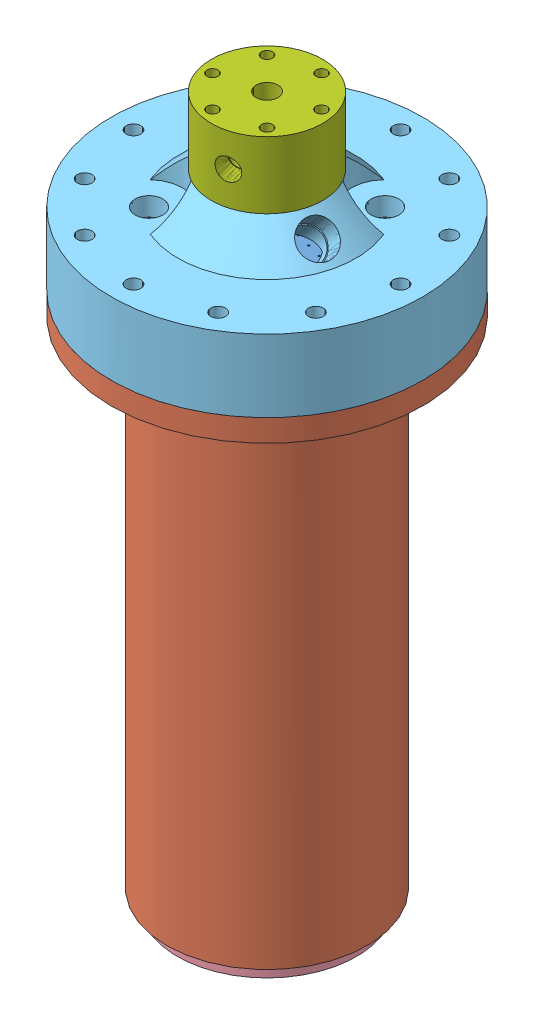
SolidWorks assembly APL1_firstEngineTest2, configuration Default. Lengths in mm.
Overall size (217.76 402.07 217.76).
9 component instances, 9 part files, 21 mates.
Components (placement in the parent):
- APL1_TopInjectorPlate-1: APL1_TopInjectorPlate [Default] at (0 15.875 0) x (0.707107 0 -0.707107) z (0.707107 0 0.707107) size (98.42 24.77 101.6)
- APL1_OuterChamberCasing-1: APL1_OuterChamberCasing [Default] at origin size (177.8 295.28 177.8)
- APL1_ablativeInsert-1: APL1_ablativeInsert [Default] at (0 -3.175 0) x (0.966975 0 -0.25487) z (0.25487 0 0.966975) size (102.26 152.4 102.26)
- APL1_graphiteInsert-1: APL1_graphiteInsert [Default] at (0 -155.575 0) x (0.995497 0 -0.094792) z (0.094792 0 0.995497) size (102.26 148.07 102.26)
- APL1_dome2-1: APL1_dome2 [Default] x (0.965926 0 0.258819) z (-0.258819 0 0.965926) size (177.8 60.32 177.8)
- APL1_LowerInjectorPlate2-1: APL1_LowerInjectorPlate2 [Default] at (0 -3.175 0) x (-0.258819 0 -0.965926) z (0.965926 0 -0.258819) size (114.3 19.05 114.3)
- APL1_ignitor1-1: APL1_ignitor1 [Default] at (0 60.325 0) x (-0.258819 0 -0.965926) z (0.965926 0 -0.258819) size (63.5 38.1 63.5)
- APL1_ignitorCore2-1: APL1_ignitorCore2 [Default] at (0 66.675 0) x (0.940112 0 -0.340865) z (0.340865 0 0.940112) size (25.4 69.85 25.4)
- APL1_Dowel2_1-1: APL1_Dowel2_1 [Default] at (11.5045 0 -42.9354) x (0.691355 0 -0.722515) z (0.722515 0 0.691355) size (3.17 28.57 3.17)
Mates (geometry in assembly coordinates):
- Concentric5: concentric aligned: cylinder of APL1_OuterChamberCasing-1 through (0 0 0) axis (0 1 0) radius 51.1302; cylinder of APL1_ablativeInsert-1 through (0 -3.175 0) axis (0 1 0) radius 51.1302
- Concentric6: concentric aligned: cylinder of APL1_OuterChamberCasing-1 through (0 0 0) axis (0 1 0) radius 51.1302; cylinder of APL1_graphiteInsert-1 through (0 -155.575 0) axis (0 1 0) radius 51.1302
- Coincident7: coincident anti-aligned: plane of APL1_ablativeInsert-1 through (-36.8418 -155.575 9.7106) normal (0 -1 0); plane of APL1_graphiteInsert-1 through (-44.5786 -155.575 4.2448) normal (0 1 0)
- Coincident8: coordinate: point of APL1_OuterChamberCasing-1
- Coincident9: coincident aligned: plane of APL1_OuterChamberCasing-1 through (-51.1302 -3.175 0) normal (0 1 0); plane of APL1_ablativeInsert-1 through (-36.8418 -3.175 9.7106) normal (0 1 0)
- Coincident10: coincident anti-aligned: plane of APL1_OuterChamberCasing-1 through (-51.1302 -3.175 0) normal (0 1 0); plane of APL1_LowerInjectorPlate2-1 through (14.7915 -3.175 55.2027) normal (0 -1 0)
- Concentric7: concentric anti-aligned: cylinder of APL1_OuterChamberCasing-1 through (0 0 0) axis (0 1 0) radius 88.9; cylinder of APL1_LowerInjectorPlate2-1 through (0 -3.175 0) axis (0 -1 0) radius 57.15
- Coincident11: coincident anti-aligned: plane of APL1_TopInjectorPlate-1 through (0 15.875 0) normal (0 -1 0); plane of APL1_LowerInjectorPlate2-1 through (3.287 15.875 12.2673) normal (0 1 0)
- Concentric8: concentric anti-aligned: cylinder of APL1_TopInjectorPlate-1 through (0 15.875 0) axis (0 -1 0) radius 50.8; cylinder of APL1_OuterChamberCasing-1 through (0 0 0) axis (0 1 0) radius 88.9
- Coincident12: coincident anti-aligned: plane of APL1_OuterChamberCasing-1 through (-57.15 0 0) normal (0 1 0); plane of APL1_dome2-1 through (-85.8708 0 -23.009) normal (0 -1 0)
- Concentric9: concentric anti-aligned: cylinder of APL1_OuterChamberCasing-1 through (0 0 0) axis (0 1 0) radius 88.9; cylinder of APL1_dome2-1 through (0 0 0) axis (0 -1 0) radius 88.9
- Concentric10: concentric aligned: cylinder of APL1_OuterChamberCasing-1 through (76.2 0 0) axis (0 1 0) radius 4.2164; cylinder of APL1_dome2-1 through (76.2 41.275 0) axis (0 1 0) radius 4.2164
- Concentric11: concentric anti-aligned: cylinder of APL1_OuterChamberCasing-1 through (0 0 0) axis (0 1 0) radius 88.9; cylinder of APL1_ignitor1-1 through (0 60.325 0) axis (0 -1 0) radius 31.75
- Coincident13: coincident anti-aligned: plane of APL1_dome2-1 through (-30.6681 60.325 -8.2175) normal (0 1 0); plane of APL1_ignitor1-1 through (3.287 60.325 12.2673) normal (0 -1 0)
- Concentric12: concentric aligned: cylinder of APL1_dome2-1 through (-6.574 60.325 24.5345) axis (0 1 0) radius 3.175; cylinder of APL1_ignitor1-1 through (-6.574 98.425 24.5345) axis (0 1 0) radius 3.175
- Concentric13: concentric aligned: cylinder of APL1_OuterChamberCasing-1 through (0 0 0) axis (0 1 0) radius 57.15; cylinder of APL1_ignitorCore2-1 through (0 66.675 0) axis (0 1 0) radius 12.7
- Coincident14: coincident anti-aligned: plane of APL1_dome2-1 through (-30.6681 60.325 -8.2175) normal (0 1 0); plane of APL1_ignitorCore2-1 through (-7.5815 60.325 2.7489) normal (0 -1 0)
- Concentric15: concentric anti-aligned: cylinder of APL1_TopInjectorPlate-1 through (11.5045 22.225 -42.9354) axis (0 1 0) radius 1.5875; cylinder of APL1_dome2-1 through (11.5045 22.225 -42.9354) axis (0 -1 0) radius 1.5875
- Concentric16: concentric aligned: cylinder of APL1_TopInjectorPlate-1 through (11.5045 22.225 -42.9354) axis (0 1 0) radius 1.5875; cylinder of APL1_LowerInjectorPlate2-1 through (11.5045 3.175 -42.9354) axis (0 1 0) radius 1.5875
- Concentric17: concentric anti-aligned: cylinder of APL1_LowerInjectorPlate2-1 through (11.5045 3.175 -42.9354) axis (0 1 0) radius 1.5875; cylinder of APL1_Dowel2_1-1 through (11.5045 28.575 -42.9354) axis (0 -1 0) radius 1.5875
- Coincident15: coincident aligned: circle of APL1_LowerInjectorPlate2-1; circle of APL1_Dowel2_1-1
